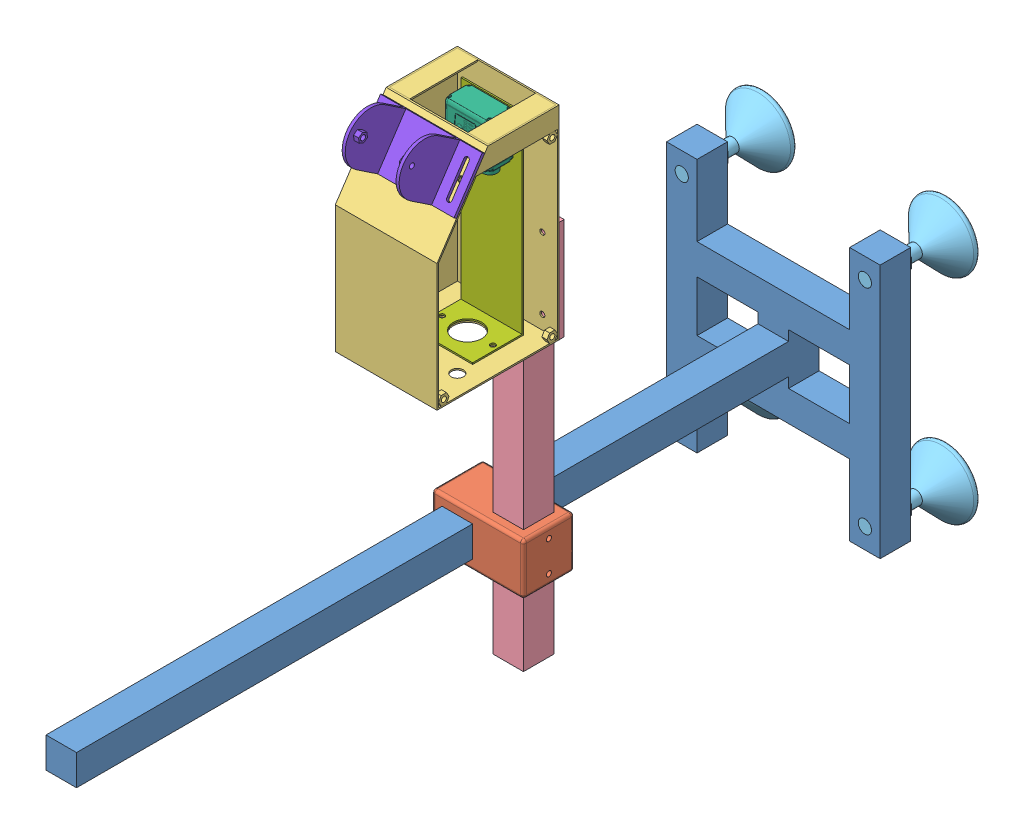
SolidWorks assembly full gia do camera, configuration Default. Lengths in mm.
Overall size (266.25 577.07 780).
11 component instances, 8 part files, 26 mates.
Components (placement in the parent):
- chan de-1: chan de [Default] at (115.5342 509.384 565.1408) size (210 250 737)
- khop noi-1: khop noi [Default] at (135.5342 509.384 855.7547) size (90 50 50)
- cover_camera-1: cover_camera [Default] at (105.5342 713.5472 895.7547) x (0 1 0) z (1 0 0) size (200 120 100)
- thanh ngang-1: thanh ngang [Default] at (155.5342 713.5472 880.7547) x (1 0 0) z (0 -1 0) size (100 30 400)
- bat_de-1: bat_de [Default] at (205.5342 404.384 515.1408) x (-0.923728 -0.383049 0) z (-0.383049 0.923728 0) size (66 80 66)
- bat_de-2: bat_de [Default] at (205.5342 614.384 515.1408) x (-0.923728 -0.383049 0) z (-0.383049 0.923728 0) size (66 80 66)
- bat_de-3: bat_de [Default] at (25.5342 404.384 515.1408) x (-0.985966 -0.166946 0) z (-0.166946 0.985966 0) size (66 80 66)
- bat_de-4: bat_de [Default] at (25.5342 614.384 515.1408) x (-0.923728 -0.383049 0) z (-0.383049 0.923728 0) size (66 80 66)
- MicroHAWK_ID-40_Drawing-1: MicroHAWK_ID-40_Drawing [Default] at (155.5342 865.5721 924.9308) x (-1 0 0) z (0 1 0) size (44.9 26.13 56.92)
- gia bat camera-1: gia bat camera [Default] at (125.5342 715.0472 910.7547) x (0 1 0) z (1 0 0) size (190 50 60)
- gia bat den-1: gia bat den [Default] at (155.5342 888.1294 982.6999) x (1 0 0) z (0 0.5547 0.83205) size (100 50 53)
Mates (geometry in assembly coordinates):
- Coincident1: coincident anti-aligned: plane of chan de-1 through (130.5342 524.384 1295.1408) normal (0 1 0); plane of khop noi-1 through (130.5342 524.384 855.7537) normal (0 -1 0)
- Coincident2: coincident anti-aligned: plane of chan de-1 through (130.5342 484.384 595.1408) normal (1 0 0); plane of khop noi-1 through (130.5342 494.384 855.7537) normal (-1 0 0)
- Coincident5: coincident anti-aligned: plane of khop noi-1 through (140.5342 484.383 865.7547) normal (1 0 0); plane of thanh ngang-1 through (140.5342 413.5472 865.7547) normal (-1 0 0)
- Coincident6: coincident anti-aligned: plane of khop noi-1 through (170.5342 484.383 895.7547) normal (0 0 -1); plane of thanh ngang-1 through (170.5342 413.5472 895.7547) normal (0 0 1)
- Coincident7: coincident anti-aligned: plane of cover_camera-1 through (205.5342 913.5472 895.7547) normal (0 0 -1); plane of thanh ngang-1 through (170.5342 413.5472 895.7547) normal (0 0 1)
- Coincident8: coincident aligned: plane of cover_camera-1 through (205.5342 713.5472 895.7547) normal (1 0 0); plane of thanh ngang-1 through (205.5342 713.5472 890.7547) normal (1 0 0)
- Coincident9: coincident aligned: plane of cover_camera-1 through (205.5342 713.5472 895.7547) normal (0 -1 0); plane of thanh ngang-1 through (105.5342 713.5472 890.7547) normal (0 -1 0)
- Concentric1: concentric aligned: cylinder of chan de-1 through (205.5342 404.384 1295.1418) axis (0 0 -1) radius 6.5238; cylinder of bat_de-1 through (205.5342 404.384 595.1408) axis (0 0 -1) radius 6.5164
- Coincident10: coincident aligned: plane of chan de-1 through (115.5342 509.384 595.1408) normal (0 0 1); plane of bat_de-1 through (205.5342 404.384 595.1408) normal (0 0 1)
- Concentric2: concentric aligned: cylinder of chan de-1 through (25.5342 404.384 1295.1418) axis (0 0 -1) radius 6.5238; cylinder of bat_de-3 through (25.5342 404.384 595.1408) axis (0 0 -1) radius 6.5164
- Coincident11: coincident aligned: plane of chan de-1 through (115.5342 509.384 595.1408) normal (0 0 1); plane of bat_de-3 through (25.5342 404.384 595.1408) normal (0 0 1)
- Coincident12: coincident aligned: plane of chan de-1 through (115.5342 509.384 595.1408) normal (0 0 1); plane of bat_de-2 through (205.5342 614.384 595.1408) normal (0 0 1)
- Concentric3: concentric aligned: cylinder of chan de-1 through (205.5342 614.384 1295.1418) axis (0 0 -1) radius 6.5238; cylinder of bat_de-2 through (205.5342 614.384 595.1408) axis (0 0 -1) radius 6.5164
- Concentric4: concentric aligned: cylinder of chan de-1 through (25.5342 614.384 1295.1418) axis (0 0 -1) radius 6.5238; cylinder of bat_de-4 through (25.5342 614.384 595.1408) axis (0 0 -1) radius 6.5164
- Coincident13: coincident aligned: plane of chan de-1 through (115.5342 509.384 595.1408) normal (0 0 1); plane of bat_de-4 through (25.5342 614.384 595.1408) normal (0 0 1)
- Parallel1: parallel anti-aligned: plane of cover_camera-1 through (205.5342 913.5472 897.2547) normal (0 0 1); plane of MicroHAWK_ID-40_Drawing-1 through (176.2592 864.8221 912.2547) normal (0 0 -1)
- Concentric5: concentric anti-aligned: cylinder of cover_camera-1 through (155.5342 913.5482 935.7547) axis (0 -1 0) radius 14; cylinder of gia bat camera-1 through (155.5342 715.0462 935.7547) axis (0 1 0) radius 14
- Concentric6: concentric anti-aligned: cylinder of cover_camera-1 through (180.5342 913.5482 935.7547) axis (0 -1 0) radius 2.5; cylinder of gia bat camera-1 through (180.5342 715.0462 935.7547) axis (0 1 0) radius 2.5
- Coincident15: coincident anti-aligned: plane of cover_camera-1 through (205.5342 715.0472 895.7547) normal (0 1 0); plane of gia bat camera-1 through (185.5342 715.0472 910.7547) normal (0 -1 0)
- Coincident16: coincident anti-aligned: plane of MicroHAWK_ID-40_Drawing-1 through (176.2592 864.8221 912.2547) normal (0 0 -1); plane of gia bat camera-1 through (185.5342 716.5472 912.2547) normal (0 0 1)
- Concentric7: concentric anti-aligned: cylinder of MicroHAWK_ID-40_Drawing-1 through (174.5342 891.0472 917.2547) axis (0 0 -1) radius 1.5; cylinder of gia bat camera-1 through (174.5342 891.0472 910.7537) axis (0 0 1) radius 1.5
- Concentric8: concentric anti-aligned: cylinder of MicroHAWK_ID-40_Drawing-1 through (174.5342 875.0472 917.2547) axis (0 0 -1) radius 1.5; cylinder of gia bat camera-1 through (174.5342 875.0472 910.7537) axis (0 0 1) radius 1.5
- Parallel4: parallel: line of cover_camera-1 through (205.5342 913.5472 965.7547) axis (-1 0 0); plane of gia bat den-1 through (205.5342 910.5947 971.3286) normal (0 0.83205 -0.5547)
- Coincident19: coincident anti-aligned: plane of cover_camera-1 through (205.5342 838.5472 1015.7547) normal (0 0.5547 0.83205); plane of gia bat den-1 through (155.5342 888.1294 982.6999) normal (0 -0.5547 -0.83205)
- Tangent2: tangent anti-aligned: cylinder of cover_camera-1 through (195.5342 794.7388 841.6253) axis (0 0.5547 0.83205) radius 2.5; plane of gia bat den-1 through (198.0342 902.2742 976.8756) normal (-1 0 0)
- Tangent3: tangent anti-aligned: cylinder of cover_camera-1 through (115.5342 794.7388 841.6253) axis (0 0.5547 0.83205) radius 2.5; plane of gia bat den-1 through (118.0342 902.2742 976.8756) normal (-1 0 0)
